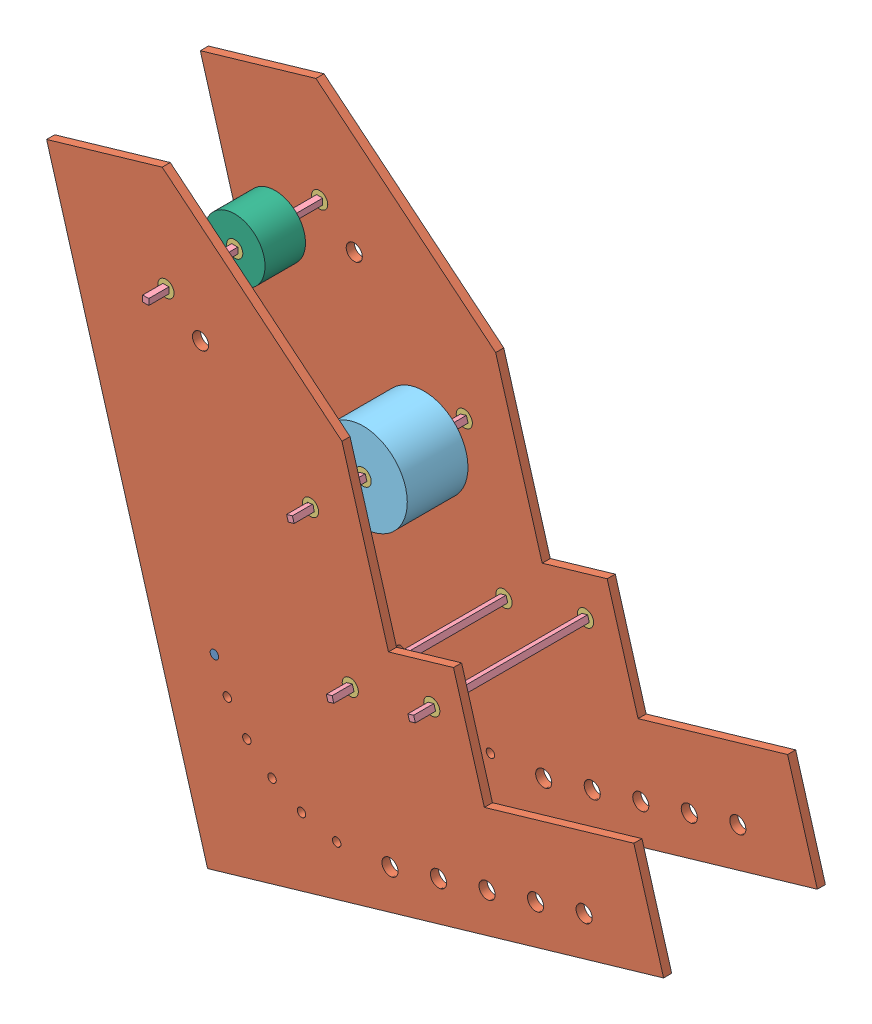
SolidWorks assembly shooter_assemble_20241130, configuration 默认. Lengths in mm.
Overall size (305.07 338.29 100).
21 component instances, 6 part files, 69 mates.
Components (placement in the parent):
- 4mmsticker-1: 4mmsticker [默认] at (0.097 0.2401 40) size (4.2 4.2 80)
- shooter_sidewall_arcylic_4mm_20241130-1: shooter_sidewall_arcylic_4mm_20241130 [默认] at (39.4442 -55.9809 116) x (0.959864 0.280464 0) z (0 0 1) size (234.9 283.8 4)
- shooter_sidewall_arcylic_4mm_20241130-2: shooter_sidewall_arcylic_4mm_20241130 [默认] at (39.4442 -55.9809 40) x (0.959864 0.280464 0) z (0 0 1) size (234.9 283.8 4)
- falon_metal_20241129-1: falon_metal_20241129 [默认] at (67.2875 19.8726 116) x (0.95991 0.280309 0) z (0 0 1) size (8 8 4)
- intaker_sticker_metal_20241129-1: intaker_sticker_metal_20241129 [默认] at (69.1478 18.8532 130) x (-0.95991 -0.280309 0) z (0 0 -1) size (3 3 100)
- falon_metal_20241129-2: falon_metal_20241129 [默认] at (67.2875 19.8726 44) x (-0.95991 -0.280309 0) z (0 0 -1) size (8 8 4)
- falon_metal_20241129-3: falon_metal_20241129 [默认] at (107.6018 31.6521 44) x (-0.95991 -0.280309 0) z (0 0 -1) size (8 8 4)
- intaker_sticker_metal_20241129-2: intaker_sticker_metal_20241129 [默认] at (109.4621 30.6327 130) x (-0.95991 -0.280309 0) z (0 0 -1) size (3 3 100)
- falon_metal_20241129-4: falon_metal_20241129 [默认] at (107.6018 31.6521 116) x (0.95991 0.280309 0) z (0 0 1) size (8 8 4)
- frictiongear-1: frictiongear [默认] at (47.655 87.0631 64) x (0.615332 -0.788268 0) z (0 0 1) size (43.64 43.64 30)
- falon_metal_20241129-5: falon_metal_20241129 [默认] at (47.655 87.0631 90) x (0.959774 0.280775 0) z (0 0 1) size (8 8 4)
- falon_metal_20241129-6: falon_metal_20241129 [默认] at (47.655 87.0631 64) size (8 8 4)
- falon_metal_20241129-7: falon_metal_20241129 [默认] at (47.655 87.0631 116) size (8 8 4)
- intaker_sticker_metal_20241129-3: intaker_sticker_metal_20241129 [默认] at (46.6365 85.2023 30) x (0.959774 0.280775 0) z (0 0 1) size (3 3 100)
- falon_metal_20241129-8: falon_metal_20241129 [默认] at (47.655 87.0631 40) x (0.959774 0.280775 0) z (0 0 1) size (8 8 4)
- frictiongear_small-1: frictiongear_small [默认] at (-23.8478 144.954 76) size (30 30 20)
- falon_metal_20241129-17: falon_metal_20241129 [默认] at (-23.8478 144.954 82) size (8 8 4)
- intaker_sticker_metal_20241129-7: intaker_sticker_metal_20241129 [默认] at (-25.3478 143.454 30) size (3 3 100)
- falon_metal_20241129-18: falon_metal_20241129 [默认] at (-23.8478 144.954 40) size (8 8 4)
- falon_metal_20241129-19: falon_metal_20241129 [默认] at (-23.8478 144.954 116) size (8 8 4)
- falon_metal_20241129-20: falon_metal_20241129 [默认] at (-23.8478 144.954 66) size (8 8 4)
Mates (geometry in assembly coordinates):
- 同心1: concentric aligned: cylinder of 4mmsticker-1 through (0.097 0.2401 120) axis (0 0 -1) radius 2.1; cylinder of shooter_sidewall_arcylic_4mm_20241130-1 through (0.097 0.2401 120) axis (0 0 -1) radius 2.1
- 重合1: coincident aligned: plane of 4mmsticker-1 through (0.097 0.2401 120) normal (0 0 1); plane of shooter_sidewall_arcylic_4mm_20241130-1 through (39.4442 -55.9809 120) normal (0 0 1)
- 同心2: concentric aligned: cylinder of 4mmsticker-1 through (0.097 0.2401 120) axis (0 0 -1) radius 2.1; cylinder of shooter_sidewall_arcylic_4mm_20241130-2 through (0.097 0.2401 44) axis (0 0 -1) radius 2.1
- 重合2: coincident aligned: plane of 4mmsticker-1 through (0.097 0.2401 40) normal (0 0 -1); plane of shooter_sidewall_arcylic_4mm_20241130-2 through (39.4442 -55.9809 40) normal (0 0 -1)
- 同心3: concentric aligned: cylinder of shooter_sidewall_arcylic_4mm_20241130-1 through (67.2875 19.8726 120) axis (0 0 -1) radius 4; cylinder of falon_metal_20241129-1 through (67.2875 19.8726 120) axis (0 0 -1) radius 4
- 重合3: coincident aligned: plane of shooter_sidewall_arcylic_4mm_20241130-1 through (39.4442 -55.9809 120) normal (0 0 1); plane of falon_metal_20241129-1 through (67.2875 19.8726 120) normal (0 0 1)
- 重合4: coincident anti-aligned: plane of intaker_sticker_metal_20241129-1 through (69.1478 18.8532 30) normal (0.280309 -0.95991 0); plane of falon_metal_20241129-2 through (69.1478 18.8532 40) normal (-0.280309 0.95991 0)
- 重合5: coincident anti-aligned: plane of intaker_sticker_metal_20241129-1; plane of falon_metal_20241129-2
- 重合7: coincident anti-aligned: plane of falon_metal_20241129-1 through (69.1478 18.8532 120) normal (-0.95991 -0.280309 0); plane of intaker_sticker_metal_20241129-1 through (69.1478 18.8532 30) normal (0.95991 0.280309 0)
- 重合8: coincident anti-aligned: plane of falon_metal_20241129-1 through (65.4272 20.892 120) normal (0.280309 -0.95991 0); plane of intaker_sticker_metal_20241129-1 through (68.3069 21.7329 30) normal (-0.280309 0.95991 0)
- 距离1: distance = 10 mm aligned: plane of shooter_sidewall_arcylic_4mm_20241130-1 through (39.4442 -55.9809 120) normal (0 0 1); plane of intaker_sticker_metal_20241129-1 through (69.1478 18.8532 130) normal (0 0 1)
- 平行1: parallel aligned: plane of shooter_sidewall_arcylic_4mm_20241130-2 through (39.4442 -55.9809 40) normal (0 0 -1); plane of falon_metal_20241129-2 through (67.2875 19.8726 40) normal (0 0 -1)
- 重合11: coincident aligned: plane of shooter_sidewall_arcylic_4mm_20241130-2 through (39.4442 -55.9809 40) normal (0 0 -1); plane of falon_metal_20241129-2 through (67.2875 19.8726 40) normal (0 0 -1)
- 重合12: coincident anti-aligned: plane of intaker_sticker_metal_20241129-2 through (108.6212 33.5124 30) normal (-0.280309 0.95991 0); plane of falon_metal_20241129-4 through (105.7415 32.6715 120) normal (0.280309 -0.95991 0)
- 重合13: coincident anti-aligned: plane of falon_metal_20241129-3 through (109.4621 30.6327 40) normal (-0.280309 0.95991 0); plane of intaker_sticker_metal_20241129-2 through (109.4621 30.6327 30) normal (0.280309 -0.95991 0)
- 重合14: coincident anti-aligned: plane of falon_metal_20241129-3; plane of intaker_sticker_metal_20241129-2
- 重合15: coincident anti-aligned: plane of intaker_sticker_metal_20241129-2 through (109.4621 30.6327 30) normal (0.95991 0.280309 0); plane of falon_metal_20241129-4 through (109.4621 30.6327 120) normal (-0.95991 -0.280309 0)
- 重合16: coincident aligned: circle of shooter_sidewall_arcylic_4mm_20241130-1; circle of falon_metal_20241129-4
- 重合17: coincident: line of intaker_sticker_metal_20241129-2 through (105.7415 32.6715 30) axis (0 0 1); plane of falon_metal_20241129-4 through (105.7415 32.6715 120) normal (0.280309 -0.95991 0)
- 重合18: coincident anti-aligned: plane of intaker_sticker_metal_20241129-2; plane of falon_metal_20241129-4
- 重合19: coincident aligned: plane of shooter_sidewall_arcylic_4mm_20241130-1 through (39.4442 -55.9809 120) normal (0 0 1); plane of falon_metal_20241129-4 through (107.6018 31.6521 120) normal (0 0 1)
- 重合20: coincident aligned: plane of shooter_sidewall_arcylic_4mm_20241130-2 through (39.4442 -55.9809 40) normal (0 0 -1); plane of falon_metal_20241129-3 through (107.6018 31.6521 40) normal (0 0 -1)
- 重合22: coincident aligned: plane of shooter_sidewall_arcylic_4mm_20241130-2 through (39.4442 -55.9809 40) normal (0 0 -1); plane of falon_metal_20241129-3 through (107.6018 31.6521 40) normal (0 0 -1)
- 重合23: coincident anti-aligned: plane of intaker_sticker_metal_20241129-2 through (108.6212 33.5124 30) normal (-0.280309 0.95991 0); plane of falon_metal_20241129-4 through (105.7415 32.6715 120) normal (0.280309 -0.95991 0)
- 距离3: distance = 10 mm aligned: plane of intaker_sticker_metal_20241129-2 through (109.4621 30.6327 130) normal (0 0 1); plane of falon_metal_20241129-4 through (107.6018 31.6521 120) normal (0 0 1)
- 重合26: coincident aligned: circle of frictiongear-1; circle of falon_metal_20241129-5
- 重合27: coincident aligned: plane of frictiongear-1 through (47.655 87.0631 94) normal (0 0 1); plane of falon_metal_20241129-5 through (47.655 87.0631 94) normal (0 0 1)
- 重合28: coincident aligned: circle of frictiongear-1; circle of falon_metal_20241129-6
- 重合29: coincident aligned: plane of frictiongear-1 through (47.655 87.0631 64) normal (0 0 -1); plane of falon_metal_20241129-6 through (47.655 87.0631 64) normal (0 0 -1)
- 同心4: concentric aligned: cylinder of shooter_sidewall_arcylic_4mm_20241130-1 through (47.655 87.0631 120) axis (0 0 -1) radius 4; cylinder of falon_metal_20241129-7 through (47.655 87.0631 120) axis (0 0 -1) radius 4
- 重合30: coincident aligned: plane of shooter_sidewall_arcylic_4mm_20241130-1 through (39.4442 -55.9809 120) normal (0 0 1); plane of falon_metal_20241129-7 through (47.655 87.0631 120) normal (0 0 1)
- 重合31: coincident aligned: circle of shooter_sidewall_arcylic_4mm_20241130-2; circle of falon_metal_20241129-8
- 重合32: coincident aligned: plane of shooter_sidewall_arcylic_4mm_20241130-2 through (39.4442 -55.9809 40) normal (0 0 -1); plane of falon_metal_20241129-8 through (47.655 87.0631 40) normal (0 0 -1)
- 重合33: coincident anti-aligned: plane of intaker_sticker_metal_20241129-3 through (45.7942 88.0816 130) normal (-0.280775 0.959774 0); plane of falon_metal_20241129-8 through (45.7942 88.0816 44) normal (0.280775 -0.959774 0)
- 重合34: coincident anti-aligned: plane of intaker_sticker_metal_20241129-3 through (46.6365 85.2023 130) normal (-0.959774 -0.280775 0); plane of falon_metal_20241129-8 through (46.6365 85.2023 44) normal (0.959774 0.280775 0)
- 重合35: coincident anti-aligned: plane of falon_metal_20241129-5 through (46.6365 85.2023 94) normal (-0.280775 0.959774 0); plane of intaker_sticker_metal_20241129-3 through (46.6365 85.2023 130) normal (0.280775 -0.959774 0)
- 重合36: coincident anti-aligned: plane of falon_metal_20241129-5 through (49.5158 86.0446 94) normal (-0.959774 -0.280775 0); plane of intaker_sticker_metal_20241129-3 through (49.5158 86.0446 130) normal (0.959774 0.280775 0)
- 重合38: coincident anti-aligned: circle of shooter_sidewall_arcylic_4mm_20241130-2; circle of falon_metal_20241129-3
- 重合39: coincident anti-aligned: circle of shooter_sidewall_arcylic_4mm_20241130-2; circle of falon_metal_20241129-2
- 距离4: distance = 10 mm aligned: plane of intaker_sticker_metal_20241129-3 through (46.6365 85.2023 130) normal (0 0 1); plane of shooter_sidewall_arcylic_4mm_20241130-1 through (39.4442 -55.9809 120) normal (0 0 1)
- 距离5: distance = 22 mm anti-aligned: plane of frictiongear-1 through (47.655 87.0631 94) normal (0 0 1); plane of shooter_sidewall_arcylic_4mm_20241130-1 through (39.4442 -55.9809 116) normal (0 0 -1)
- 重合45: coincident aligned: plane of falon_metal_20241129-15 through (455.8207 346.8543 1195.8373) normal (0 0 -1); plane of shooter_sidewall_arcylic_4mm_20241130-3 through (427.9774 271.0008 1195.8373) normal (0 0 -1)
- 平行2: parallel aligned: plane of falon_metal_20241129-15 through (455.8207 346.8543 1195.8373) normal (0 0 -1); plane of shooter_sidewall_arcylic_4mm_20241130-3 through (427.9774 271.0008 1195.8373) normal (0 0 -1)
- 重合61: coincident aligned: plane of falon_metal_20241129-12 through (436.1881 414.0448 1249.8373) normal (0 0 1); plane of frictiongear-2 through (436.1881 414.0448 1249.8373) normal (0 0 1)
- 重合63: coincident anti-aligned: plane of intaker_sticker_metal_20241129-4 through (435.1696 412.184 1285.8373) normal (0.280775 -0.959774 0); plane of falon_metal_20241129-12 through (435.1696 412.184 1249.8373) normal (-0.280775 0.959774 0)
- 重合64: coincident aligned: circle of falon_metal_20241129-11; circle of frictiongear-2
- 重合65: coincident aligned: circle of falon_metal_20241129-12; circle of frictiongear-2
- 重合66: coincident aligned: plane of falon_metal_20241129-11 through (436.1881 414.0448 1219.8373) normal (0 0 -1); plane of frictiongear-2 through (436.1881 414.0448 1219.8373) normal (0 0 -1)
- 重合68: coincident anti-aligned: plane of falon_metal_20241129-9 through (434.3273 415.0633 1199.8373) normal (0.280775 -0.959774 0); plane of intaker_sticker_metal_20241129-4 through (434.3273 415.0633 1285.8373) normal (-0.280775 0.959774 0)
- 重合69: coincident anti-aligned: plane of falon_metal_20241129-9 through (435.1696 412.184 1199.8373) normal (0.959774 0.280775 0); plane of intaker_sticker_metal_20241129-4 through (435.1696 412.184 1285.8373) normal (-0.959774 -0.280775 0)
- 重合70: coincident aligned: circle of falon_metal_20241129-9; circle of shooter_sidewall_arcylic_4mm_20241130-3
- 重合71: coincident aligned: plane of falon_metal_20241129-9 through (436.1881 414.0448 1195.8373) normal (0 0 -1); plane of shooter_sidewall_arcylic_4mm_20241130-3 through (427.9774 271.0008 1195.8373) normal (0 0 -1)
- 重合72: coincident anti-aligned: plane of intaker_sticker_metal_20241129-4 through (438.049 413.0263 1285.8373) normal (0.959774 0.280775 0); plane of falon_metal_20241129-12 through (438.049 413.0263 1249.8373) normal (-0.959774 -0.280775 0)
- 重合73: coincident anti-aligned: circle of falon_metal_20241129-15; circle of shooter_sidewall_arcylic_4mm_20241130-3
- 重合86: coincident anti-aligned: plane of intaker_sticker_metal_20241129-7 through (-25.3478 143.454 130) normal (0 -1 0); plane of falon_metal_20241129-19 through (-25.3478 143.454 120) normal (0 1 0)
- 重合87: coincident anti-aligned: plane of intaker_sticker_metal_20241129-7 through (-22.3478 143.454 130) normal (1 0 0); plane of falon_metal_20241129-19 through (-22.3478 143.454 120) normal (-1 0 0)
- 距离10: distance = 10 mm aligned: plane of intaker_sticker_metal_20241129-7 through (-25.3478 143.454 130) normal (0 0 1); plane of falon_metal_20241129-19 through (-23.8478 144.954 120) normal (0 0 1)
- 重合89: coincident anti-aligned: plane of intaker_sticker_metal_20241129-7 through (-25.3478 143.454 130) normal (-1 0 0); plane of falon_metal_20241129-18 through (-25.3478 143.454 44) normal (1 0 0)
- 重合90: coincident anti-aligned: plane of intaker_sticker_metal_20241129-7 through (-25.3478 143.454 130) normal (0 -1 0); plane of falon_metal_20241129-18 through (-25.3478 143.454 44) normal (0 1 0)
- 距离11: distance = 10 mm aligned: plane of falon_metal_20241129-18 through (-23.8478 144.954 40) normal (0 0 -1); plane of intaker_sticker_metal_20241129-7 through (-25.3478 143.454 30) normal (0 0 -1)
- 重合92: coincident aligned: plane of frictiongear_small-1 through (-23.8478 144.954 -33.1184) normal (0 0 -1); plane of falon_metal_20241129-20 through (-23.8478 144.954 -33.1184) normal (0 0 -1)
- 同心9: concentric aligned: cylinder of frictiongear_small-1 through (-23.8478 144.954 -13.1184) axis (0 0 -1) radius 4; cylinder of falon_metal_20241129-20 through (-23.8478 144.954 -29.1184) axis (0 0 -1) radius 4
- 同心10: concentric aligned: cylinder of frictiongear_small-1 through (-23.8478 144.954 -13.1184) axis (0 0 -1) radius 4; cylinder of falon_metal_20241129-17 through (-23.8478 144.954 -13.1184) axis (0 0 -1) radius 4
- 重合93: coincident aligned: plane of frictiongear_small-1 through (-23.8478 144.954 -13.1184) normal (0 0 1); plane of falon_metal_20241129-17 through (-23.8478 144.954 -13.1184) normal (0 0 1)
- 重合94: coincident anti-aligned: plane of falon_metal_20241129-17 through (-25.3478 143.454 -13.1184) normal (0 1 0); plane of intaker_sticker_metal_20241129-7 through (-25.3478 143.454 130) normal (0 -1 0)
- 重合95: coincident anti-aligned: plane of falon_metal_20241129-17 through (-22.3478 143.454 -13.1184) normal (-1 0 0); plane of intaker_sticker_metal_20241129-7 through (-22.3478 143.454 130) normal (1 0 0)
- 同心11: concentric aligned: cylinder of shooter_sidewall_arcylic_4mm_20241130-1 through (-23.8478 144.954 120) axis (0 0 -1) radius 4; cylinder of falon_metal_20241129-19 through (-23.8478 144.954 120) axis (0 0 -1) radius 4
- 重合97: coincident aligned: plane of shooter_sidewall_arcylic_4mm_20241130-1 through (39.4442 -55.9809 120) normal (0 0 1); plane of falon_metal_20241129-19 through (-23.8478 144.954 120) normal (0 0 1)
- 距离12: distance = 30 mm anti-aligned: plane of frictiongear_small-1 through (-23.8478 144.954 86) normal (0 0 1); plane of shooter_sidewall_arcylic_4mm_20241130-1 through (39.4442 -55.9809 116) normal (0 0 -1)
